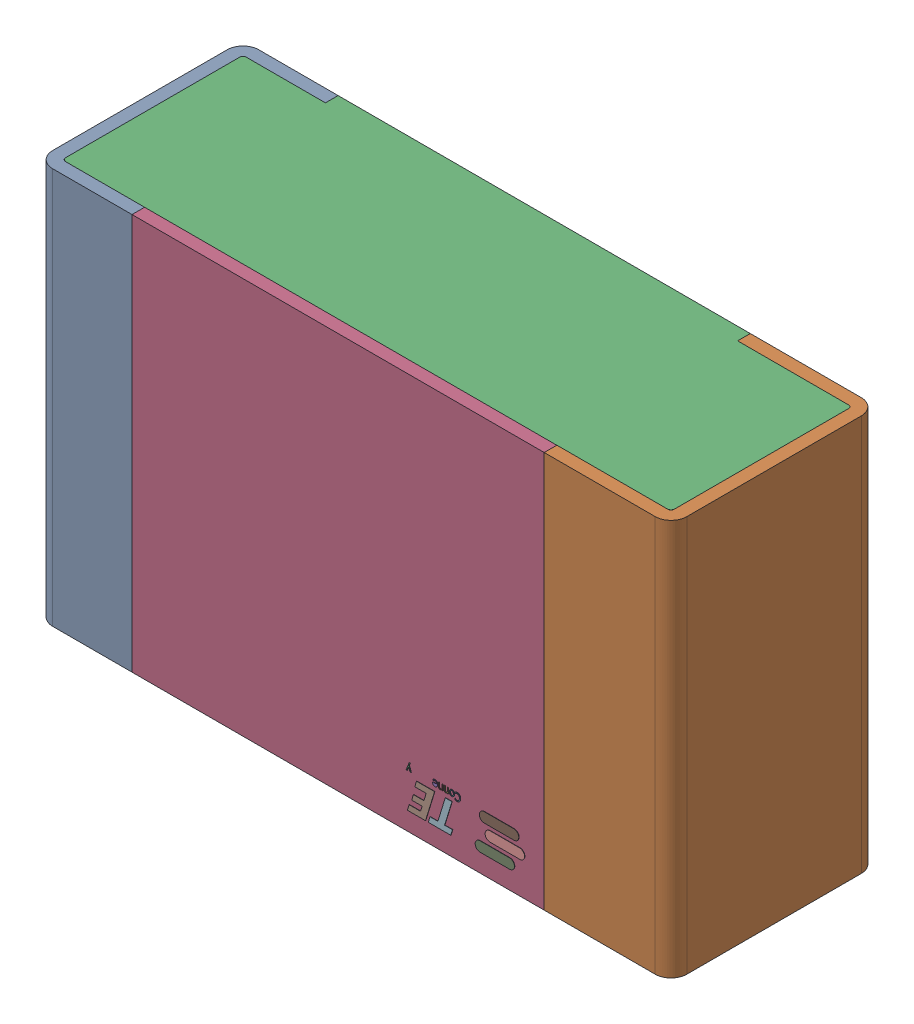
SolidWorks assembly RLL4.step, configuration Default. Lengths in mm.
Overall size (2 1.25 0.65).
5 component instances, 4 part files, 0 mates.
Components (placement in the parent):
- Res_TE_Connectivity_CPF0805B66R5E1_eec.step-1: Res_TE_Connectivity_CPF0805B66R5E1_eec.step [Default] at (10.287 10.287 0) x (-1 0 0) z (0 0 1) size (2 1.25 0.65)
  - 1.step-1: 1.step [Default] at origin size (2 1.25 0.65)
  - 2.step-1: 2.step [Default] at origin size (1.92 1.25 0.61)
  - 3.step-1: 3.step [Default] at origin size (1.3 1.25 0.04)
  - TE connectivity Logo 1 (2).step-1: TE connectivity Logo 1 (2).step [Default] at (5.4285 0.313 0.551) x (-1 0 0) z (0 0 1) size (0.37 0.13 0.11)
